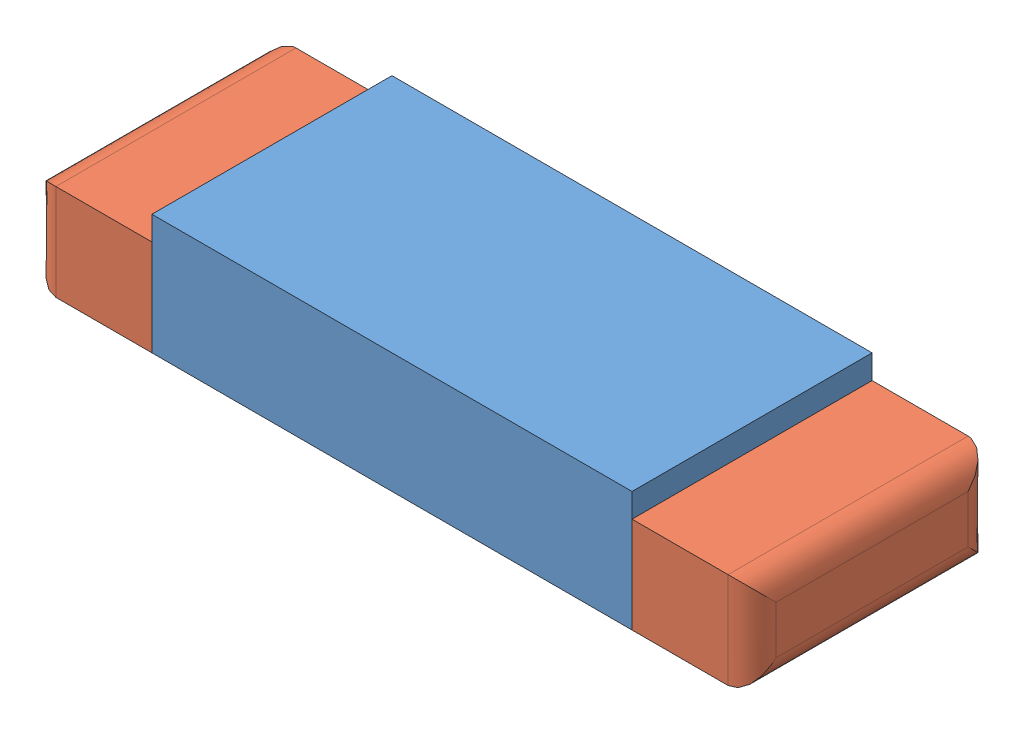
SolidWorks assembly Assemblage3, configuration Défaut. Lengths in mm.
Overall size (3 0.5 1).
3 component instances, 2 part files, 6 mates.
Components (placement in the parent):
- CMS_Corps-1: CMS_Corps [Défaut] at (-26.1967 2.7319 0.5) size (2 0.5 1)
- CMS_soud-1: CMS_soud [Défaut] at (-24.1967 2.7319 0.5) size (0.5 0.4 1)
- CMS_soud-2: CMS_soud [Défaut] at (-26.1967 2.7319 -0.5) x (-1 0 0) z (0 0 -1) size (0.5 0.4 1)
Mates (geometry in assembly coordinates):
- Coïncidente1: coincident anti-aligned: plane of CMS_Corps-1; plane of CMS_soud-1
- Coïncidente2: coincident aligned: plane of CMS_Corps-1; plane of CMS_soud-1
- Coïncidente3: coincident aligned: plane of CMS_Corps-1; plane of CMS_soud-1
- Coïncidente4: coincident anti-aligned: plane of CMS_Corps-1; plane of CMS_soud-2
- Coïncidente5: coincident aligned: plane of CMS_Corps-1; plane of CMS_soud-2
- Coïncidente6: coincident aligned: plane of CMS_Corps-1; plane of CMS_soud-2
